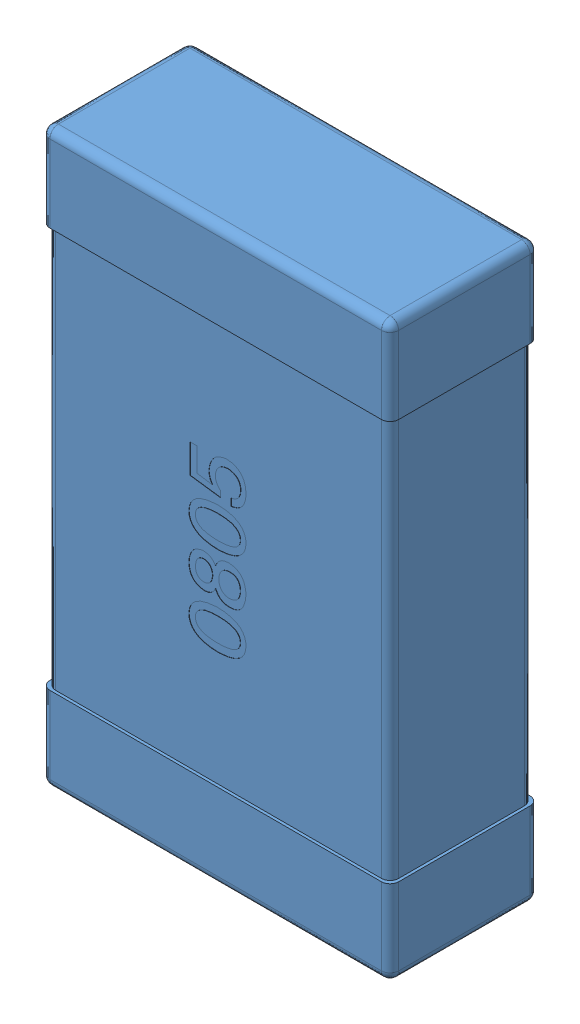
SolidWorks assembly 0805电容, configuration 默认. Lengths in mm.
Overall size (1.22 2 0.52).
2 component instances, 1 part files, 0 mates.
Components (placement in the parent):
- C_0805^0805电容-1: C_0805^0805电容 [默认] at (59.563 77.597 0) x (0 1 0) z (0 0 1) size (2 1.22 0.52) (virtual)
  - C_0805-5^C_0805_0805电容-1: C_0805-5^C_0805_0805电容 [默认] at origin size (2 1.22 0.52) (virtual)
